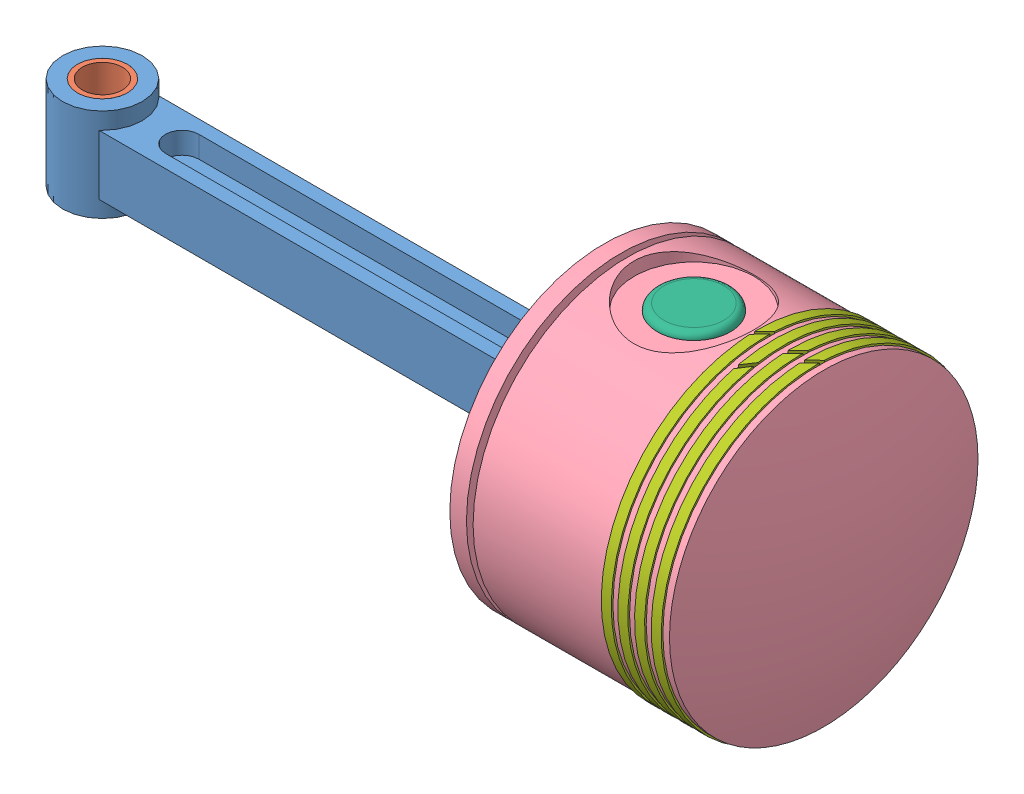
SolidWorks assembly articulated rod assembly, configuration Default. Lengths in mm.
Overall size (234.91 111.75 111.87).
12 component instances, 7 part files, 8 mates.
Components (placement in the parent):
- articulated_rod-1: articulated_rod [Default] at (7.0676 119.2405 140.5577) size (207.5 42 35)
- rod_bush_lower-1: rod_bush_lower [Default] at (7.0676 109.2405 140.5577) size (15 24 15)
- rod_upper_bush-1: rod_upper_bush [Default] at (185.0676 119.2405 140.5577) size (24 42 24)
- piston assembly-1: piston assembly [Default] at (131.2592 208.9985 122.3335) x (-0.001757 0 -0.999998) z (0 -1 0) size (111.75 71.81 111.75)
  - piston-2: piston [Default] at (-18.3187 26.7763 89.758) size (93 71.81 93)
  - piston_pin-2: piston_pin [Default] at (-18.3187 53.7763 88.258) x (0.998755 -0.049893 0) z (-0.049893 -0.998755 0) size (22 80 22)
  - piston_plug-3: piston_plug [Default] at (-18.3187 53.7763 116.258) x (1 0 0) z (0 -1 0) size (22 15 22)
  - piston_ring-2: piston_ring [Default] at (-18.3187 74.2763 89.758) size (94 3 94)
  - piston_plug-4: piston_plug [Default] at (-18.3187 53.7763 60.258) x (-0.837169 0.546944 0) z (-0.546944 -0.837169 0) size (22 15 22)
  - piston_ring-3: piston_ring [Default] at (-18.3187 89.2763 89.758) size (94 3 94)
  - piston_ring-6: piston_ring [Default] at (-18.3187 79.2763 89.758) x (0.977406 0 -0.211373) z (0.211373 0 0.977406) size (94 3 94)
  - piston_ring-7: piston_ring [Default] at (-18.3187 84.2763 89.758) size (94 3 94)
Mates (geometry in assembly coordinates):
- Concentric1: concentric aligned: circle of articulated_rod-1; circle of rod_bush_lower-1
- Coincident2: coincident aligned: circle of articulated_rod-1; circle of rod_bush_lower-1
- Concentric4: concentric aligned: circle of articulated_rod-1; circle of rod_upper_bush-1
- Coincident3: coincident aligned: circle of articulated_rod-1; circle of rod_upper_bush-1
- Concentric5: concentric anti-aligned: cylinder of rod_upper_bush-1 through (185.0676 140.2405 140.5577) axis (0 -1 0) radius 11; cylinder of piston assembly-1/piston_pin-2 through (185.0676 80.7405 140.5577) axis (0 1 0) radius 11
- Concentric6: concentric anti-aligned: circle of articulated_rod-1; circle of piston assembly-1/piston-2
- Distance1: distance = 4 mm anti-aligned: plane of piston assembly-1/piston-2 through (185.0676 94.2405 140.5577) normal (0 1 0); plane of articulated_rod-1 through (7.0676 98.2405 140.5577) normal (0 -1 0)
- LimitAngle2: limit planar angle = 1.572554 rad aligned: plane of articulated_rod-1 through (7.0676 128.2405 131.5577) normal (0 0 -1); plane of piston assembly-1/piston-2 through (158.0677 119.2405 140.6051) normal (-0.999998 0 0.001757)
